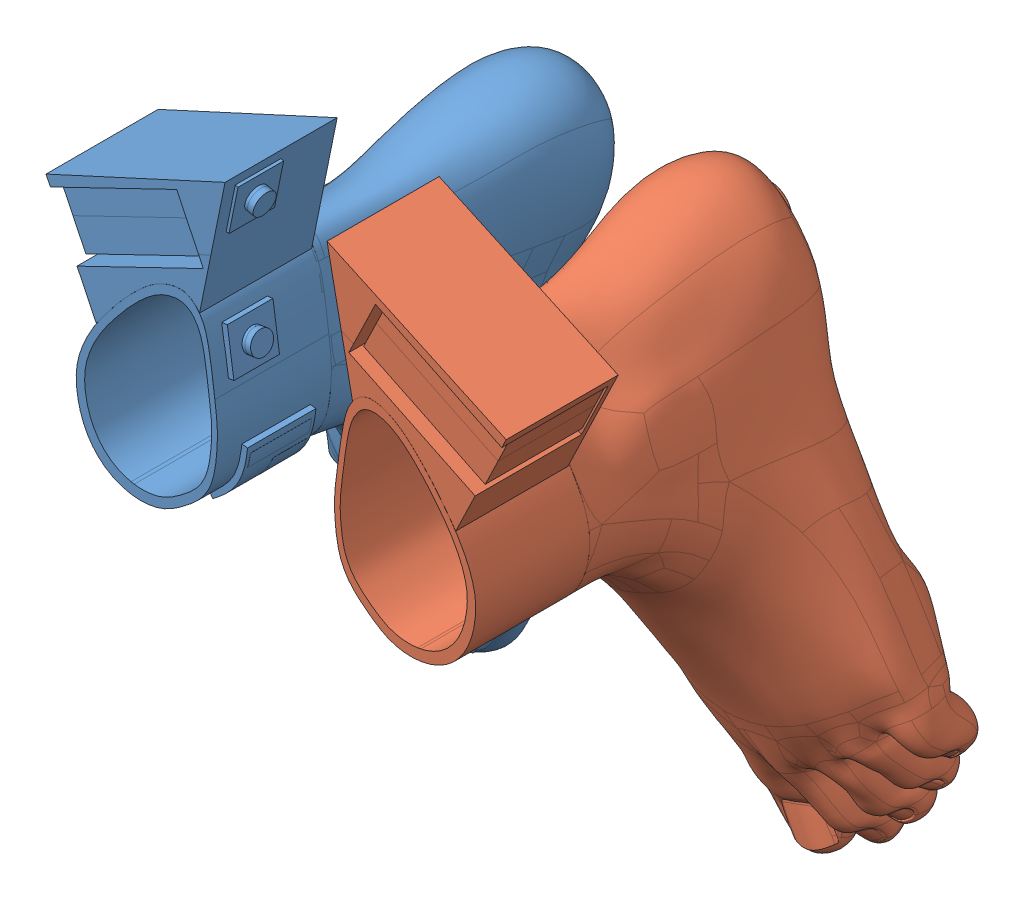
SolidWorks assembly Feet_plain, configuration Default. Lengths in mm.
Overall size (546.46 568.46 358.41).
3 component instances, 3 part files, 0 mates.
Components (placement in the parent):
- foot1-1: foot1 [Right] at (256.4291 194.2322 323.4055) size (245.52 568.46 358.41)
- Mirrorfoot1-2: Mirrorfoot1 [Right] at (383.5709 194.2322 323.4055) x (-1 0 0) z (0 0 -1) (suppressed, hidden)
- Mirrorfoot1-4: Mirrorfoot1 [Right] at (223.5709 194.2322 323.4055) x (-1 0 0) z (0 0 -1) size (245.52 568.46 358.41)
